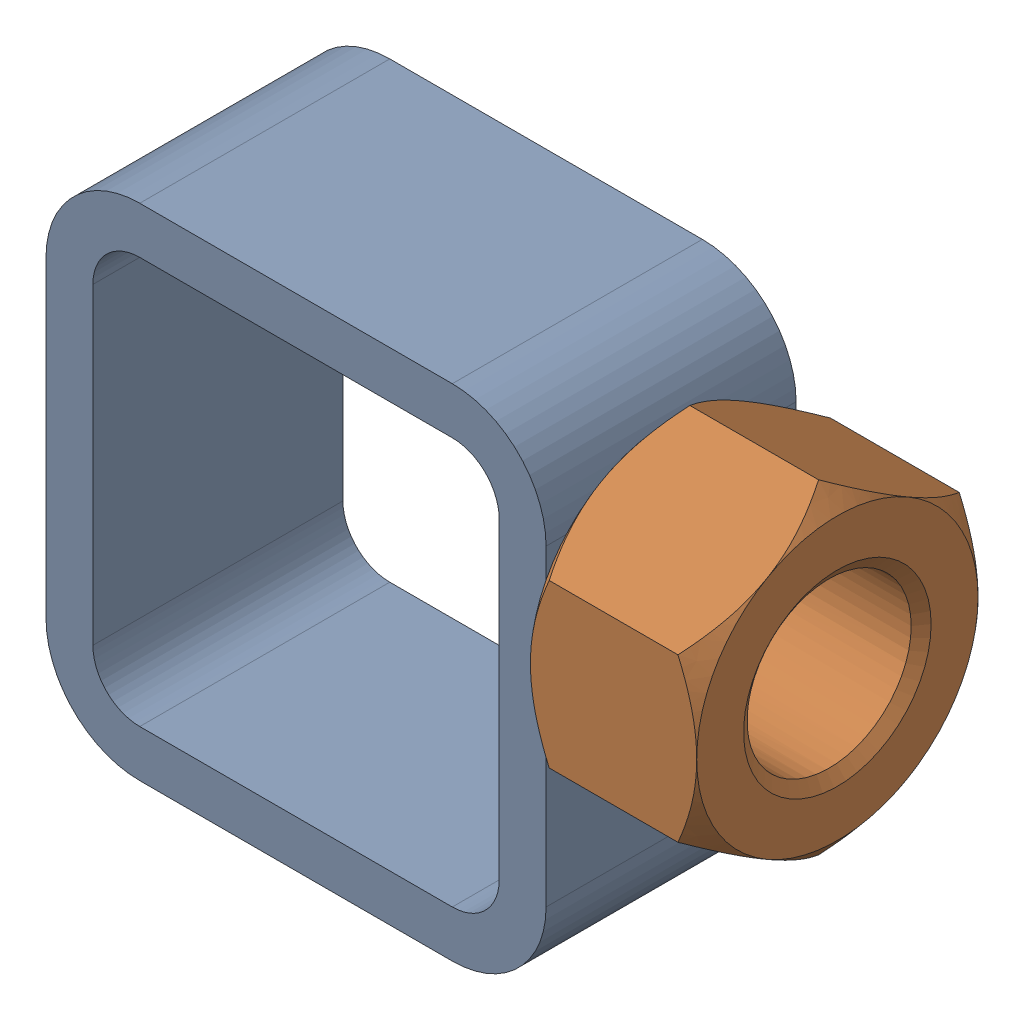
SolidWorks assembly 01-005-00-0-6, configuration Default. Lengths in mm.
Overall size (67.69 50.8 28.57).
2 component instances, 2 part files, 0 mates.
Components (placement in the parent):
- tube square_ai(PreviewCfg)-1: tube square_ai(PreviewCfg) [Default] at origin size (50.8 50.8 25.4)
- hex nut_ai(HNUT 0.7500-10-D-C)-1: hex nut_ai(HNUT 0.7500-10-D-C) [Default] at (67.691 31.75 0) x (0 0 -1) z (1 0 0) size (28.57 33 16.89)
